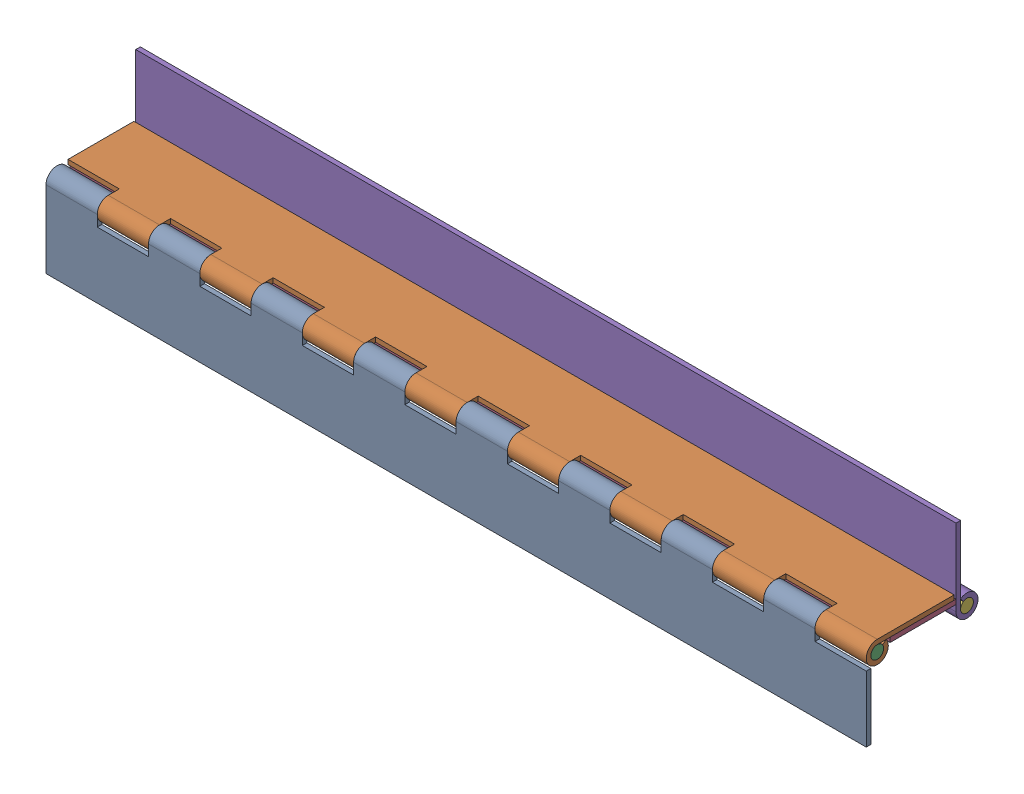
SolidWorks assembly FE-00004-07_ASM, configuration Default. Lengths in mm.
Overall size (406.4 73.91 55.37).
6 component instances, 4 part files, 0 mates.
Components (placement in the parent):
- FE-00004-07-A_1-1: FE-00004-07-A_1 [Default] at origin size (406.4 43.56 10.92)
- FE-00004-07-A_AF2-1: FE-00004-07-A_AF2 [Default] at (0 5.461 -5.461) x (-1 0 0) z (0 1 0) size (406.4 43.56 10.92)
- FE-00004-07-B_1-1: FE-00004-07-B_1 [Default] at (0 0 -5.461) size (406.4 6.35 6.35)
- FE-00004-07-A_AF3-1: FE-00004-07-A_AF3 [Default] at (0 3.175 -49.911) x (1 0 0) z (0 1 0) size (406.4 43.56 10.92)
- FE-00004-07-A_1-2: FE-00004-07-A_1 [Default] at (0 -2.286 -44.45) x (-1 0 0) z (0 0 1) size (406.4 43.56 10.92)
- FE-00004-07-B_1-2: FE-00004-07-B_1 [Default] at (0 -2.286 -49.911) size (406.4 6.35 6.35)
